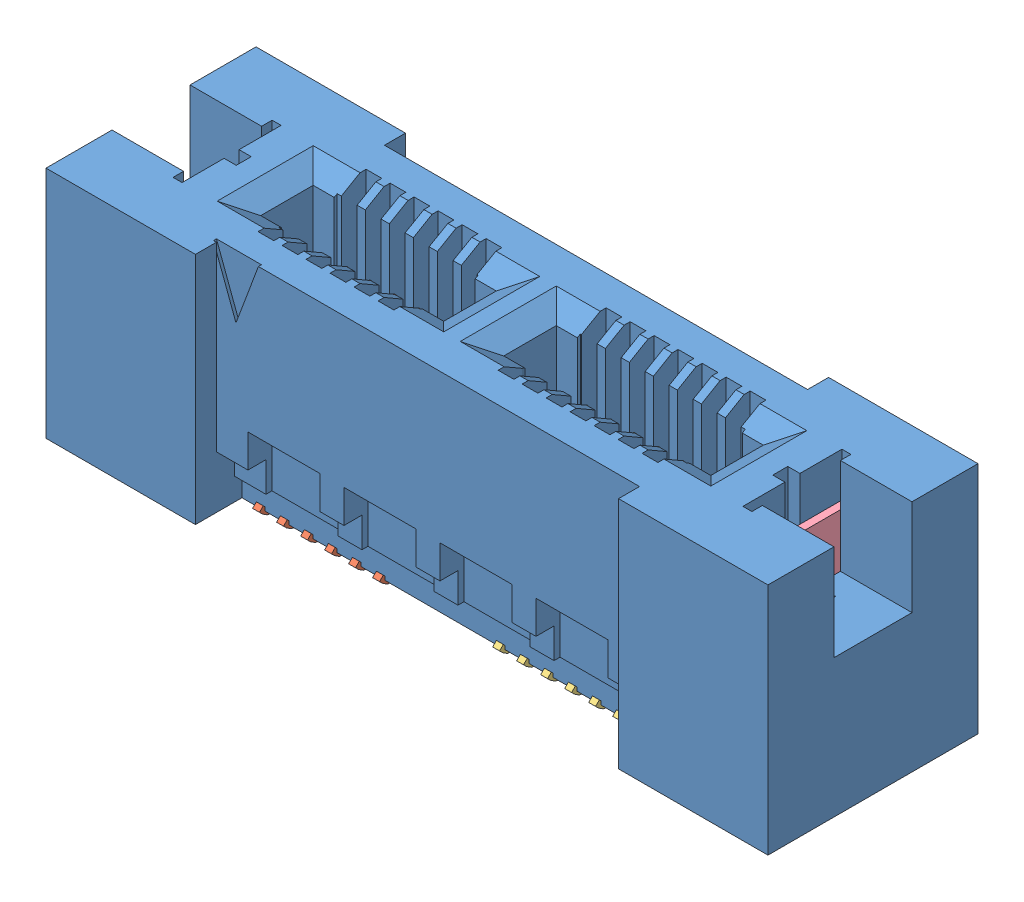
SolidWorks assembly HSEC8_113_01_L_DV_L2, configuration Default. Lengths in mm.
Overall size (24.06 9.28 7).
5 component instances, 4 part files, 0 mates.
Components (placement in the parent):
- _HSEC8_113_01_L_DV_L2ter_2-1: _HSEC8_113_01_L_DV_L2ter_2 [Default] at origin size (24.06 7.8 7)
- _C_188_02_Pin_6_01_4-1: _C_188_02_Pin_6_01_4 [Default] at (-6.4 -0.183 0) x (0 0 1) z (-1 0 0) size (4.26 5.75 4.58)
- _C_188_02_Pin_7_01_6-1: _C_188_02_Pin_7_01_6 [Default] at (1.6 -0.183 0) x (0 0 1) z (-1 0 0) size (4.26 5.75 5.38)
- _WT_25_09_Latching_Option_L2_8-1: _WT_25_09_Latching_Option_L2_8 [Default] at (-9.495 6.355 0) x (0 0 -1) z (1 0 0) size (3.3 7.84 0.25)
- _WT_25_09_Latching_Option_L2_8-2: _WT_25_09_Latching_Option_L2_8 [Default] at (9.495 6.355 0) x (0 0 -1) z (1 0 0) size (3.3 7.84 0.25)
